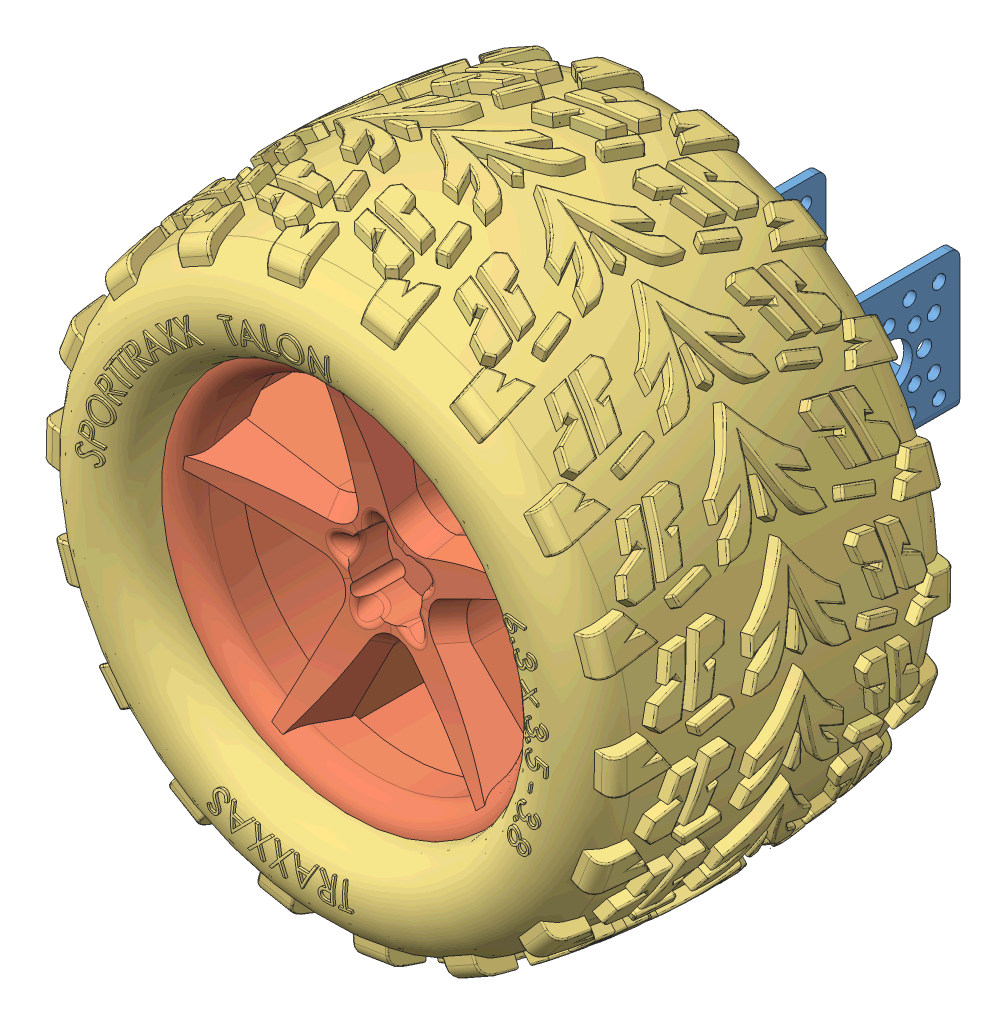
SolidWorks assembly Wheel Assembly, configuration Middle Wheel. Lengths in mm.
Overall size (223.53 223.71 157.75).
16 component instances, 9 part files, 26 mates.
Components (placement in the parent):
- 3 Aluminum Channel-1: 3 Aluminum Channel [Default] at (-17.2943 0 0) size (38.1 38.1 76.2)
- Wheel-1: Wheel [Default] at (-96.6519 -37.2227 110.0113) x (0 0 1) z (0.454033 0.890985 0) size (106.88 166.05 166.47)
  - Wheel Rim-1: Wheel Rim [Default] at (-5.7009 62.13 94.8184) size (78.74 101.6 101.6)
  - Wheel Tire-1: Wheel Tire [Default] at (-5.7009 62.1295 94.8183) size (106.88 166.05 166.47)
- 25m Bore Side Tapped Clamping Mount-1: 25m Bore Side Tapped Clamping Mount [Default] at (1.1407 25.2168 75.4549) x (1 0 0) z (0 -1 0) size (33.76 7.62 39.7)
  - 25m Bore Side Tapped Clamping Mount-1: 25m Bore Side Tapped Clamping Mount [Default] at (0.615 -8.6446 6.1668) size (33.76 7.62 39.7)
  - #6-32 0_5 Bolt-1: #6-32 0_5 Bolt [Default] at (-31.135 -4.8346 -13.2719) x (0 0.2706 0.962692) z (-1 0 0) size (5.57 5.57 16.21)
- 25mm Motor and Encoder-1: 25mm Motor and Encoder [Default] at (-28.8188 23.347 73.4354) x (0.990268 -0.139173 0) z (0 0 1) size (25 32.85 80)
- 6-32_SHCS-1: 6-32_SHCS [6-32 SHCS X .250] at (14.4557 32.5204 70.6204) x (0 0 -1) z (1 0 0) (suppressed, hidden)
- 6-32_SHCS-2: 6-32_SHCS [6-32 SHCS X .250] at (-10.9443 32.5204 70.6204) x (0 0.924225 0.381849) z (-1 0 0) (suppressed, hidden)
- 6-32_SHCS-3: 6-32_SHCS [6-32 SHCS X .250] at (-10.9443 5.5796 70.6204) x (0 0.924225 0.381849) z (-1 0 0) (suppressed, hidden)
- 6-32_SHCS-4: 6-32_SHCS [6-32 SHCS X .250] at (14.4557 5.5796 70.6204) x (0 0 -1) z (1 0 0) (suppressed, hidden)
- 4mm Face Tapped Clamping Hub-1: 4mm Face Tapped Clamping Hub [Default] at (1.7557 19.05 94.7854) x (0.999441 -0.033438 0) z (-0.033438 -0.999441 0) size (20.57 9.64 26.29)
- 6-32_SHCS-5: 6-32_SHCS [6-32 SHCS X 1.250] at (8.8978 25.7297 103.1072) x (-0.454033 -0.890985 0) z (0 0 1) (suppressed, hidden)
- 6-32_SHCS-6: 6-32_SHCS [6-32 SHCS X 1.250] at (-5.3865 12.3703 103.1072) x (-0.454033 -0.890985 0) z (0 0 1) (suppressed, hidden)
- wheel shell-1: wheel shell [Default] at (1.7557 19.05 150.9911) x (0.998715 -0.050671 0) z (-0.050671 -0.998715 0) size (165.1 2.54 165.1) (hidden)
Mates (geometry in assembly coordinates):
- Concentric1: concentric aligned: cylinder of Wheel-1/Wheel Rim-1 through (-5.3865 12.3703 174.3702) axis (0 0 -1) radius 1.905; cylinder of 6-32_SHCS-6 through (-5.3865 12.3703 178.247) axis (0 0 -1) radius 2.8702
- Concentric2: concentric aligned: cylinder of Wheel-1/Wheel Rim-1 through (8.8978 25.7297 174.3702) axis (0 0 -1) radius 1.905; cylinder of 6-32_SHCS-5 through (8.8978 25.7297 178.247) axis (0 0 -1) radius 2.8702
- Concentric3: concentric anti-aligned: cylinder of 25m Bore Side Tapped Clamping Mount-1/25m Bore Side Tapped Clamping Mount-1 through (1.7557 19.05 74.4304) axis (0 0 -1) radius 12.5; cylinder of 25mm Motor and Encoder-1 through (1.7557 19.05 66.8104) axis (0 0 1) radius 12.5
- Concentric4: concentric anti-aligned: cylinder of 25mm Motor and Encoder-1 through (1.7557 19.05 91.8104) axis (0 0 1) radius 2; cylinder of 4mm Face Tapped Clamping Hub-1 through (1.7557 19.05 94.7854) axis (0 0 -1) radius 2
- Coincident1: coincident aligned: plane of 25mm Motor and Encoder-1 through (1.7557 19.05 104.3104) normal (0 0 1); plane of 4mm Face Tapped Clamping Hub-1 through (1.7557 19.05 104.3104) normal (0 0 1)
- Coincident2: coincident aligned: plane of 25m Bore Side Tapped Clamping Mount-1/25m Bore Side Tapped Clamping Mount-1 through (15.2253 5.5804 66.8104) normal (0 0 -1); plane of 25mm Motor and Encoder-1 through (1.7557 19.05 66.8104) normal (0 0 -1)
- Concentric5: concentric anti-aligned: cylinder of 3 Aluminum Channel-1 through (20.8057 32.5204 70.6204) axis (1 0 0) radius 1.778; cylinder of 25m Bore Side Tapped Clamping Mount-1/25m Bore Side Tapped Clamping Mount-1 through (-15.0083 32.5204 70.6204) axis (-1 0 0) radius 1.3526
- Concentric6: concentric anti-aligned: cylinder of 3 Aluminum Channel-1 through (20.8057 5.5796 70.6204) axis (1 0 0) radius 1.778; cylinder of 25m Bore Side Tapped Clamping Mount-1/25m Bore Side Tapped Clamping Mount-1 through (-15.0083 5.5796 70.6204) axis (-1 0 0) radius 1.3526
- Coincident3: coincident anti-aligned: plane of 3 Aluminum Channel-1 through (18.5197 2.286 76.2) normal (-1 0 0); plane of 25m Bore Side Tapped Clamping Mount-1/25m Bore Side Tapped Clamping Mount-1 through (18.5197 35.6946 74.4304) normal (1 0 0)
- Concentric7: concentric anti-aligned: cylinder of 3 Aluminum Channel-1 through (20.8057 32.5204 101.3102) axis (1 0 0) radius 1.778; cylinder of 6-32_SHCS-1 through (33.5057 32.5204 101.3102) axis (-1 0 0) radius 2.8702
- Concentric8: concentric aligned: cylinder of 3 Aluminum Channel-1 through (20.8057 32.5204 101.3102) axis (1 0 0) radius 1.778; cylinder of 6-32_SHCS-2 through (-29.9943 32.5204 101.3102) axis (1 0 0) radius 2.8702
- Concentric9: concentric anti-aligned: cylinder of 3 Aluminum Channel-1 through (20.8057 5.5796 101.3102) axis (1 0 0) radius 1.778; cylinder of 6-32_SHCS-4 through (33.5057 5.5796 101.3102) axis (-1 0 0) radius 2.8702
- Concentric10: concentric aligned: cylinder of 3 Aluminum Channel-1 through (20.8057 5.5796 101.3102) axis (1 0 0) radius 1.778; cylinder of 6-32_SHCS-3 through (-29.9943 5.5796 101.3102) axis (1 0 0) radius 2.8702
- Coincident4: coincident anti-aligned: plane of 3 Aluminum Channel-1 through (-17.2943 0 106.8898) normal (-1 0 0); plane of 6-32_SHCS-2 through (-17.2943 32.5204 101.3102) normal (1 0 0)
- Coincident5: coincident anti-aligned: plane of 3 Aluminum Channel-1 through (-17.2943 0 106.8898) normal (-1 0 0); plane of 6-32_SHCS-3 through (-17.2943 5.5796 101.3102) normal (1 0 0)
- Coincident6: coincident anti-aligned: plane of 3 Aluminum Channel-1 through (20.8057 38.1 106.8898) normal (1 0 0); plane of 6-32_SHCS-4 through (20.8057 5.5796 101.3102) normal (-1 0 0)
- Coincident7: coincident anti-aligned: plane of 3 Aluminum Channel-1 through (20.8057 38.1 106.8898) normal (1 0 0); plane of 6-32_SHCS-1 through (20.8057 32.5204 101.3102) normal (-1 0 0)
- Coincident8: coincident anti-aligned: moEndPointRef_w of Wheel-1/Wheel Rim-1; plane of 6-32_SHCS-6 through (-5.3865 12.3703 165.547) normal (0 0 -1)
- Coincident9: coincident anti-aligned: moEndPointRef_w of Wheel-1/Wheel Rim-1; plane of 6-32_SHCS-5 through (8.8978 25.7297 165.547) normal (0 0 -1)
- Concentric11: concentric anti-aligned: cylinder of 4mm Face Tapped Clamping Hub-1 through (8.8978 25.7297 135.0002) axis (0 0 1) radius 1.3526; cylinder of 6-32_SHCS-5 through (8.8978 25.7297 178.247) axis (0 0 -1) radius 2.8702
- Concentric12: concentric anti-aligned: cylinder of 4mm Face Tapped Clamping Hub-1 through (-5.3865 12.3703 135.0002) axis (0 0 1) radius 1.3526; cylinder of 6-32_SHCS-6 through (-5.3865 12.3703 178.247) axis (0 0 -1) radius 2.8702
- Tangent1: tangent: face of Wheel-1/Wheel Rim-1; plane of 4mm Face Tapped Clamping Hub-1 through (1.7557 19.05 104.3104) normal (0 0 1)
- Parallel1: parallel aligned: plane of 3 Aluminum Channel-1 through (-17.2943 0 76.2) normal (-1 0 0); plane of 25mm Motor and Encoder-1 through (-4.5443 22.9901 30.0104) normal (-1 0 0)
- Concentric13: concentric anti-aligned: cylinder of Wheel-1/Wheel Rim-1 through (1.7557 19.05 64.9404) axis (0 0 1) radius 1.9685; cylinder of wheel shell-1 through (1.7557 19.05 153.5311) axis (0 0 -1) radius 82.55
- Coincident10: coincident anti-aligned: plane of 3 Aluminum Channel-1 through (20.8057 0 76.2) normal (0 -1 0); plane of assembly through (0 0 0) normal (0 1 0)
- Coincident11: coincident anti-aligned: plane of 3 Aluminum Channel-1 through (-17.2943 0 0) normal (0 0 -1); plane of assembly through (0 0 0) normal (0 0 1)
